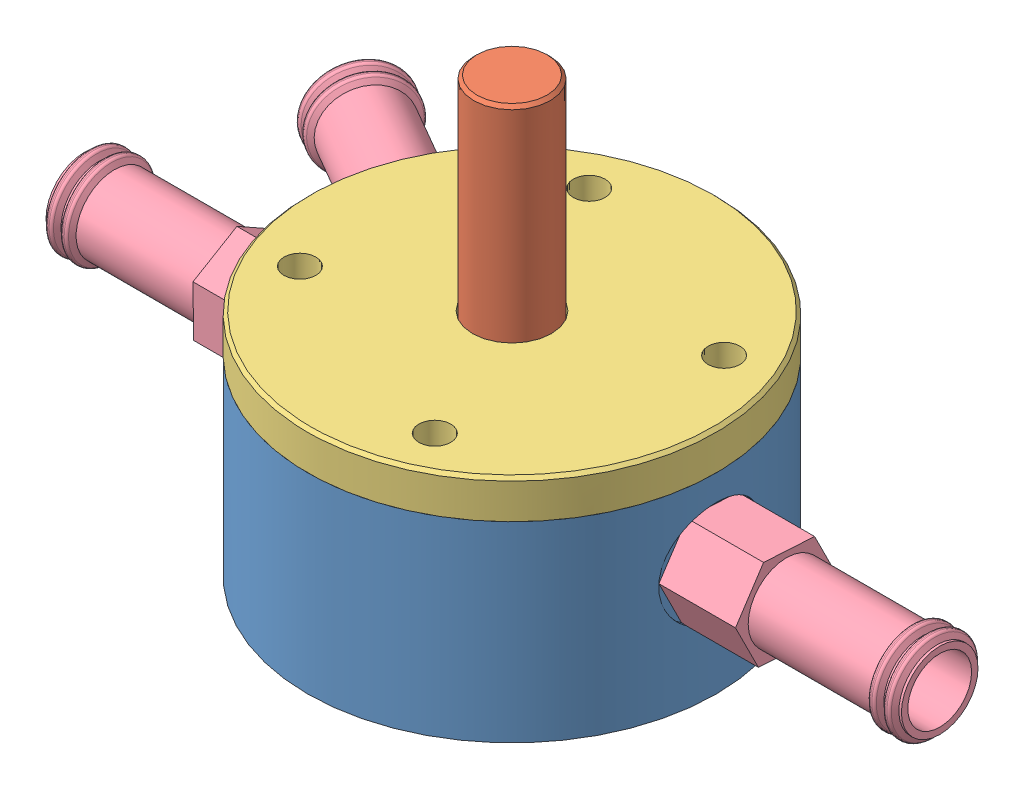
SolidWorks assembly Montagem_Shutter_v11, configuration Default. Lengths in mm.
Overall size (67 34.5 36.14).
7 component instances, 5 part files, 16 mates.
Components (placement in the parent):
- Sede_Inferior_v11-1: Sede_Inferior_v11 [Valor predeterminado<Como usinado>] at origin size (32 15 32)
- Desviador_v10-1: Desviador_v10 [Valor predeterminado] x (-0.869205 0 -0.494452) z (0.494452 0 -0.869205) size (18 34.5 18)
- Sede_superior_v9-1: Sede_superior_v9 [Valor predeterminado] at (0 7.5 0) size (32 4 32)
- Conexao reta_v11-1: Conexao reta_v11 [Valor predeterminado] at (19 0 0) x (-1 0 0) z (0 -0.835237 0.54989) size (22 7 8)
- Conexao reta_v11-3: Conexao reta_v11 [Valor predeterminado] at (-16.4545 0 -9.5) x (0.866025 0 0.5) z (0.055025 0.993926 -0.095307) size (22 7 8)
- Conexao reta_v11-5: Conexao reta_v11 [Valor predeterminado] at (-19 0 0) x (1 0 0) z (0 0.999933 0.011568) size (22 7 8)
- Vedacao_Tangencial-2: Vedacao_Tangencial [Valor predeterminado] at origin size (20 11 20)
Mates (geometry in assembly coordinates):
- Coincident1: coordinate: point of ?
- Concentric1: concentric aligned: cylinder of Sede_Inferior_v11-1 through (0 -9 0) axis (0 -1 0) radius 3; cylinder of Desviador_v10-1 through (0 0 0) axis (0 -1 0) radius 3
- Coincident2: coincident anti-aligned: plane of Sede_Inferior_v11-1 through (9 -5 0) normal (0 1 0); plane of Desviador_v10-1 through (-2.6076 -5 -1.4834) normal (0 -1 0)
- Concêntrico1: concentric aligned: cylinder of Desviador_v10-1 through (0 0 0) axis (0 -1 0) radius 3; cylinder of Sede_superior_v9-1 through (0 7.5 0) axis (0 -1 0) radius 3.1
- Coincidente3: coincident anti-aligned: plane of Sede_superior_v9-1 through (9 6 0) normal (0 -1 0); plane of Sede_Inferior_v11-1 through (0 6 0) normal (0 1 0)
- Concêntrico4: concentric aligned: cylinder of Sede_Inferior_v11-1 through (5.2827 6 11.3288) axis (0 1 0) radius 1.25; cylinder of Sede_superior_v9-1 through (5.2827 9 11.3288) axis (0 1 0) radius 1.25
- Concêntrico5: concentric anti-aligned: cylinder of Sede_Inferior_v11-1 through (16 0 0) axis (1 0 0) radius 2.25; cylinder of Conexao reta_v11-5 through (-48.7219 0 0) axis (-1 0 0) radius 2.25
- Concêntrico6: concentric aligned: cylinder of Sede_Inferior_v11-1 through (-13.8564 0 -8) axis (-0.866025 0 -0.5) radius 2.25; cylinder of Conexao reta_v11-3 through (-42.1944 0 -24.361) axis (-0.866025 0 -0.5) radius 2.25
- Concêntrico7: concentric anti-aligned: cylinder of Sede_Inferior_v11-1 through (-16 0 0) axis (-1 0 0) radius 2.25; cylinder of Conexao reta_v11-1 through (48.7219 0 0) axis (1 0 0) radius 2.25
- Coincidente4: coincident anti-aligned: plane of Sede_Inferior_v11-1 through (-13.4234 0 -7.75) normal (-0.866025 0 -0.5); plane of Conexao reta_v11-3 through (-11.4355 -0.4402 -11.1931) normal (0.866025 0 0.5)
- Coincidente5: coincident anti-aligned: plane of Sede_Inferior_v11-1 through (-15.5 0 0) normal (-1 0 0); plane of Conexao reta_v11-5 through (-15.5 0.0463 -3.9997) normal (1 0 0)
- Coincidente6: coincident anti-aligned: plane of Sede_Inferior_v11-1 through (15.5 0 0) normal (1 0 0); plane of Conexao reta_v11-1 through (15.5 -2.1996 -3.3409) normal (-1 0 0)
- Concêntrico11: concentric anti-aligned: cylinder of Sede_Inferior_v11-1 through (0 -16.4492 0) axis (0 1 0) radius 9.5; cylinder of ? through (0 3 0) axis (0 -1 0) radius 9
- Concêntrico12: concentric anti-aligned: cylinder of Conexao reta_v11-5 through (-46.7219 0 0) axis (-1 0 0) radius 1.75; cylinder of ? through (-9.5 0 0) axis (1 0 0) radius 2.25
- Coincidente8: coincident anti-aligned: plane of Sede_Inferior_v11-1 through (9 -5 0) normal (0 1 0); plane of Vedacao_Tangencial-2 through (0 -5 0) normal (0 -1 0)
- Concêntrico15: concentric anti-aligned: cylinder of Sede_Inferior_v11-1 through (0 -33.2843 0) axis (0 1 0) radius 10; cylinder of Vedacao_Tangencial-2 through (0 -5 0) axis (0 -1 0) radius 9
